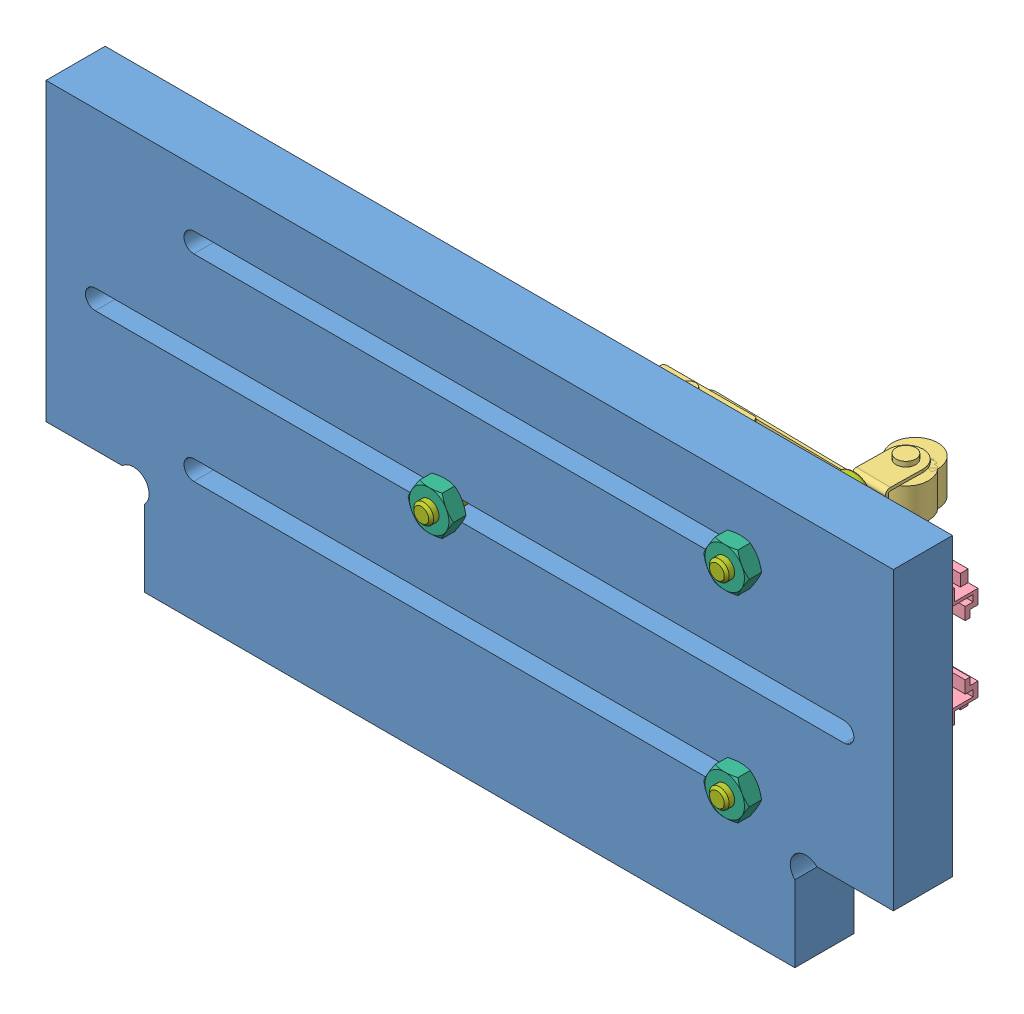
SolidWorks assembly cfc_ouvert, configuration Défaut. Lengths in mm.
Overall size (86 40 30.8).
14 component instances, 7 part files, 25 mates.
Components (placement in the parent):
- cfc-platine-1: cfc-platine [Défaut] at (140.8628 -70 0) x (0 0 1) z (0 -1 0) size (6 86 40)
- Grove microswitch v1.0-1: Grove microswitch v1.0 [Défaut] at (-27.4996 23.25 -3.344) x (-1 0 0) z (0 -1 0) size (41.8 22.4 23.6)
  - PCB grove 20x40-1: PCB grove 20x40 [Défaut] at (-1.988 -1.344 0) size (41.8 1.6 23.6)
  - microswitch 10T85-1: microswitch 10T85 [Défaut] at (9.562 0.256 0) size (22.48 22.4 6.4)
  - Connecteur Grove (coudé CMS)-1: Connecteur Grove (coudé CMS) [Défaut] at (-21.488 0.256 0) x (0 0 -1) z (0 1 0) size (12 10 5)
- entretoise-grove-1: entretoise-grove [Défaut] at (-45.5117 23.25 -2) x (1 0.000242 0) z (0 0 1) size (4 4 2)
- entretoise-grove-2: entretoise-grove [Défaut] at (-15.5117 33.25 -2) size (4 4 2)
- entretoise-grove-3: entretoise-grove [Défaut] at (-15.5117 13.25 -2) size (4 4 2)
- ecrou-h-1: ecrou-h [6007 HU M2] at (-45.5117 23.25 7.6) x (0.866025 -0.5 0) z (-0.5 -0.866025 0) size (4 1.6 4.62)
- ecrou-h-2: ecrou-h [6007 HU M2] at (-15.5117 33.25 7.6) x (0.866025 0.5 0) z (0.5 -0.866025 0) size (4 1.6 4.62)
- ecrou-h-3: ecrou-h [6007 HU M2] at (-15.5117 13.25 7.6) x (-0.866025 0.5 0) z (0.5 0.866025 0) size (4 1.6 4.62)
- vis-chc-1: vis-chc [Vis CHC M2x12] at (-15.5117 33.25 -3.6) x (1 0 0) z (0 1 0) size (3.8 14 3.8)
- vis-chc-2: vis-chc [Vis CHC M2x12] at (-15.5117 13.25 -3.6) x (1 0 0) z (0 1 0) size (3.8 14 3.8)
- vis-chc-3: vis-chc [Vis CHC M2x12] at (-45.5117 23.25 -3.6) x (0.999585 0.028802 0) z (-0.028802 0.999585 0) size (3.8 14 3.8)
Mates (geometry in assembly coordinates):
- Coaxiale1: concentric anti-aligned: cylinder of Grove microswitch v1.0-1/PCB grove 20x40-1 through (-15.5117 13.25 -3.6) axis (0 0 1) radius 1.1; cylinder of entretoise-grove-3 through (-15.5117 13.25 0) axis (0 0 -1) radius 1
- Coïncidente4: coincident anti-aligned: plane of Grove microswitch v1.0-1/PCB grove 20x40-1 through (-25.5117 23.25 -2) normal (0 0 1); plane of entretoise-grove-3 through (-15.5117 13.25 -2) normal (0 0 -1)
- Coaxiale2: concentric anti-aligned: cylinder of Grove microswitch v1.0-1/PCB grove 20x40-1 through (-45.5117 23.25 -3.6) axis (0 0 1) radius 1.1; cylinder of entretoise-grove-1 through (-45.5117 23.25 0) axis (0 0 -1) radius 1
- Coïncidente5: coincident anti-aligned: plane of Grove microswitch v1.0-1/PCB grove 20x40-1 through (-25.5117 23.25 -2) normal (0 0 1); plane of entretoise-grove-1 through (-45.5117 23.25 -2) normal (0 0 -1)
- Coaxiale3: concentric anti-aligned: cylinder of Grove microswitch v1.0-1/PCB grove 20x40-1 through (-15.5117 33.25 -3.6) axis (0 0 1) radius 1.1; cylinder of entretoise-grove-2 through (-15.5117 33.25 0) axis (0 0 -1) radius 1
- Coïncidente6: coincident anti-aligned: plane of Grove microswitch v1.0-1/PCB grove 20x40-1 through (-25.5117 23.25 -2) normal (0 0 1); plane of entretoise-grove-2 through (-15.5117 33.25 -2) normal (0 0 -1)
- Coïncidente7: coincident anti-aligned: plane of cfc-platine-1 through (-8.8686 8.8686 0) normal (0 0 -1); plane of entretoise-grove-1 through (-45.5117 23.25 0) normal (0 0 1)
- Parallèle4: parallel aligned: plane of cfc-platine-1 through (-86 40 6) normal (-1 0 0); plane of Grove microswitch v1.0-1/PCB grove 20x40-1 through (-45.5117 23.25 -3.6) normal (-1 0 0)
- Parallèle3: parallel aligned: plane of cfc-platine-1 through (-10 0 6) normal (0 -1 0); plane of Grove microswitch v1.0-1/PCB grove 20x40-1 through (-25.5117 13.25 -3.6) normal (0 -1 0)
- Coaxiale4: concentric anti-aligned: cylinder of Grove microswitch v1.0-1/PCB grove 20x40-1 through (-15.5117 33.25 -3.6) axis (0 0 1) radius 1.1; cylinder of vis-chc-1 through (-15.5117 33.25 8.4) axis (0 0 -1) radius 1
- Coaxiale5: concentric anti-aligned: cylinder of Grove microswitch v1.0-1/PCB grove 20x40-1 through (-45.5117 23.25 -3.6) axis (0 0 1) radius 1.1; cylinder of vis-chc-3 through (-45.5117 23.25 8.4) axis (0 0 -1) radius 1
- Coaxiale6: concentric anti-aligned: cylinder of Grove microswitch v1.0-1/PCB grove 20x40-1 through (-15.5117 13.25 -3.6) axis (0 0 1) radius 1.1; cylinder of vis-chc-2 through (-15.5117 13.25 8.4) axis (0 0 -1) radius 1
- Coïncidente11: coincident anti-aligned: plane of Grove microswitch v1.0-1/PCB grove 20x40-1 through (-25.5117 23.25 -3.6) normal (0 0 -1); plane of vis-chc-3 through (-45.5117 23.25 -3.6) normal (0 0 1)
- Coïncidente12: coincident anti-aligned: plane of Grove microswitch v1.0-1/PCB grove 20x40-1 through (-25.5117 23.25 -3.6) normal (0 0 -1); plane of vis-chc-2 through (-15.5117 13.25 -3.6) normal (0 0 1)
- Coïncidente13: coincident anti-aligned: plane of Grove microswitch v1.0-1/PCB grove 20x40-1 through (-25.5117 23.25 -3.6) normal (0 0 -1); plane of vis-chc-1 through (-15.5117 33.25 -3.6) normal (0 0 1)
- Coaxiale7: concentric anti-aligned: cylinder of ecrou-h-2 through (-15.5117 33.25 6) axis (0 0 1) radius 0.7835; cylinder of vis-chc-1 through (-15.5117 33.25 8.4) axis (0 0 -1) radius 1
- Coaxiale8: concentric anti-aligned: cylinder of ecrou-h-3 through (-15.5117 13.25 6) axis (0 0 1) radius 0.7835; cylinder of vis-chc-2 through (-15.5117 13.25 8.4) axis (0 0 -1) radius 1
- Coaxiale9: concentric anti-aligned: cylinder of ecrou-h-1 through (-45.5117 23.25 6) axis (0 0 1) radius 0.7835; cylinder of vis-chc-3 through (-45.5117 23.25 8.4) axis (0 0 -1) radius 1
- Coïncidente14: coincident anti-aligned: plane of cfc-platine-1 through (-8.8686 8.8686 6) normal (0 0 1); plane of ecrou-h-2 through (-14.357 35.25 6) normal (0 0 -1)
- Coïncidente15: coincident anti-aligned: plane of cfc-platine-1 through (-8.8686 8.8686 6) normal (0 0 1); plane of ecrou-h-1 through (-43.2023 23.25 6) normal (0 0 -1)
- Coïncidente16: coincident anti-aligned: plane of cfc-platine-1 through (-8.8686 8.8686 6) normal (0 0 1); plane of ecrou-h-3 through (-17.8211 13.25 6) normal (0 0 -1)
- Parallèle5: parallel aligned: plane of cfc-platine-1 through (0 40 6) normal (0 1 0); plane of ecrou-h-2 through (-14.357 35.25 6) normal (0 1 0)
- Parallèle6: parallel aligned: plane of ecrou-h-1 through (-44.357 25.25 6) normal (0 1 0); plane of ecrou-h-2 through (-14.357 35.25 6) normal (0 1 0)
- Parallèle7: parallel aligned: plane of ecrou-h-2 through (-14.357 35.25 6) normal (0 1 0); plane of ecrou-h-3 through (-14.357 15.25 6) normal (0 1 0)
- Tangent1: tangent anti-aligned: plane of cfc-platine-1 through (-15 32.25 6) normal (0 1 0); cylinder of vis-chc-1 through (-15.5117 33.25 8.4) axis (0 0 -1) radius 1
